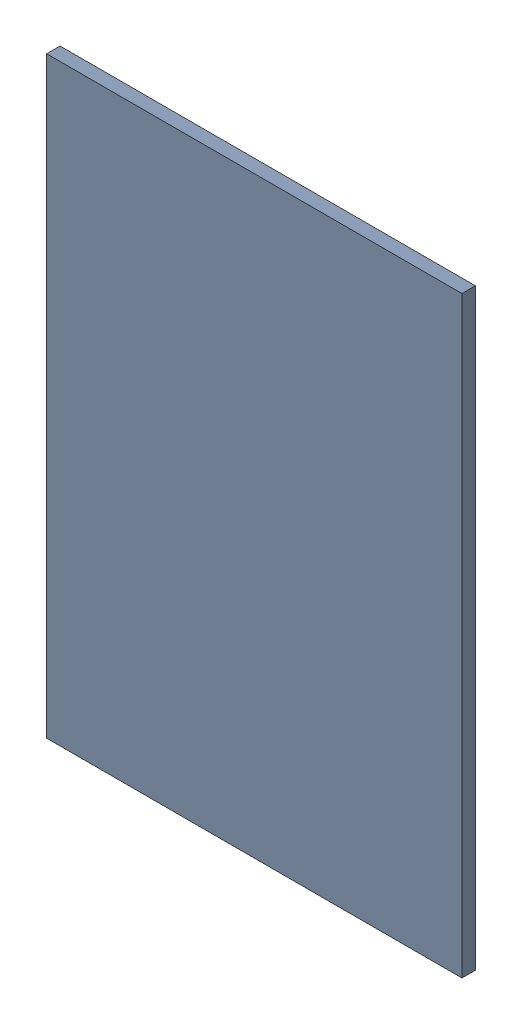
SolidWorks assembly Pad C3-1(28.81mm,48.5mm) on Top Layer, configuration Predeterminado. Lengths in mm.
Overall size (1.1 1.57 0.04).
2 component instances, 1 part files, 0 mates.
Components (placement in the parent):
- Pad C3-1(28.81mm,48.5mm) on Top Layer-1-1: Pad C3-1(28.81mm,48.5mm) on Top Layer-1 [Predeterminado] at (-68.317 -44.187 -0.0457) size (1.1 1.57 0.04)
  - Pad C3-1(28.81mm,48.5mm) on Top Layer-Part-1-1: Pad C3-1(28.81mm,48.5mm) on Top Layer-Part-1 [Predeterminado] at origin size (1.1 1.57 0.04)
